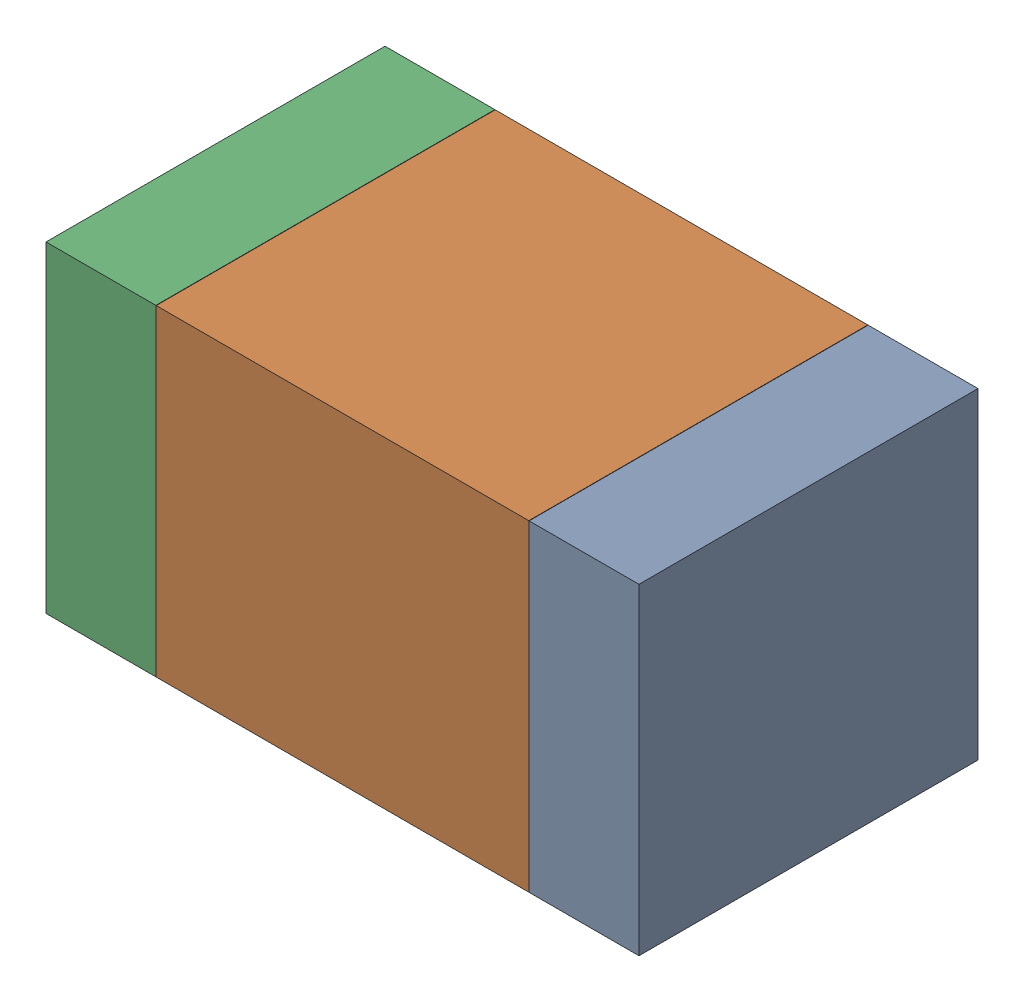
SolidWorks assembly C18, configuration Default. Lengths in mm.
Overall size (1.75 0.95 1).
6 component instances, 2 part files, 0 mates.
Components (placement in the parent):
- 6575498272-1: 6575498272 [Default] at (22.9375 22.86 0) size (0.32 0.95 1)
  - Extruded_8-1: Extruded_8 [Default] at origin size (0.32 0.95 1)
- 6575498112-1: 6575498112 [Default] at (22.225 22.86 0) size (1.1 0.95 1)
  - Extruded_9-1: Extruded_9 [Default] at origin size (1.1 0.95 1)
- 6575498272-2: 6575498272 [Default] at (21.5125 22.86 0) size (0.32 0.95 1)
  - Extruded_8-1: Extruded_8 [Default] at origin size (0.32 0.95 1)
